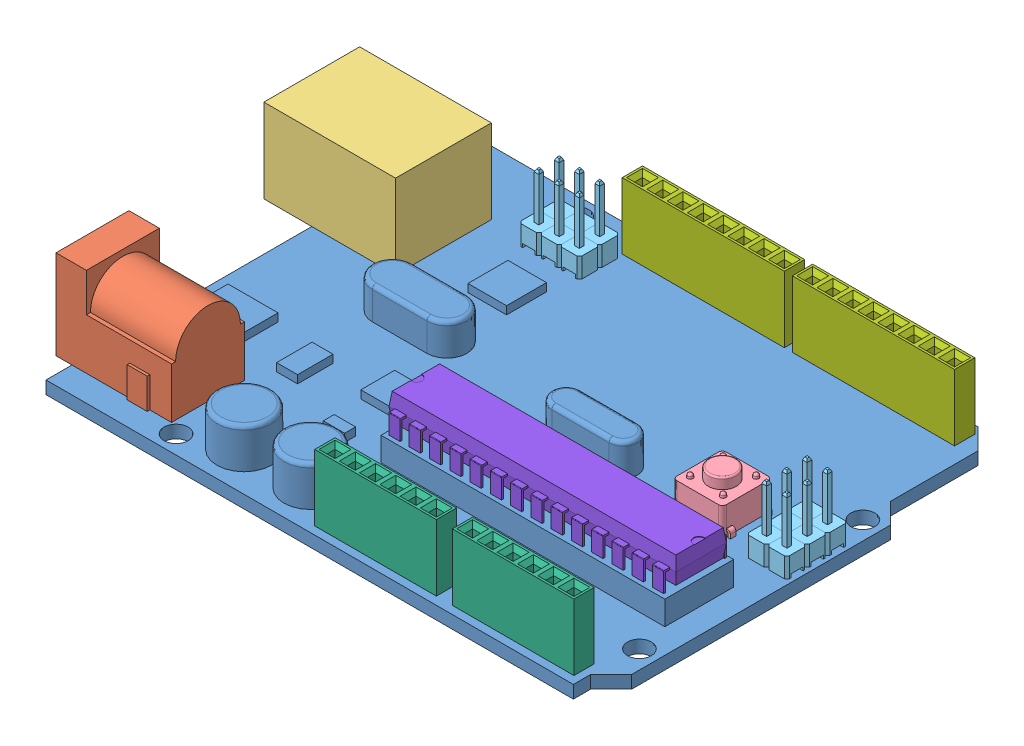
SolidWorks assembly User Library-Arduino-UNO, configuration Predeterminado. Lengths in mm.
Overall size (74.65 14.9 53.3).
15 component instances, 8 part files, 43 mates.
Components (placement in the parent):
- User Library-Arduino-UNO_Arduino_UNO_PCB-1: User Library-Arduino-UNO_Arduino_UNO_PCB [Predeterminado] at (-41.2845 -4.4325 26.65) size (68.65 6.6 53.3)
- User Library-Arduino-UNO_User Library-Arduino Mega_DC POWER JACK-1: User Library-Arduino-UNO_User Library-Arduino Mega_DC POWER JACK [Default] at (-43.2845 -2.8325 18.828) x (0 0 1) z (-1 0 0) size (9.47 14.78 14.48)
- User Library-Arduino-UNO_User Library-Arduino Mega_USB SM host-1: User Library-Arduino-UNO_User Library-Arduino Mega_USB SM host [Default] at (-39.0345 2.4175 -12.65) x (0 0 1) z (-1 0 0) size (14.86 14.22 16.5)
- User Library-Arduino-UNO_User Library-Arduino Mega_tactile BUTTON-1: User Library-Arduino-UNO_User Library-Arduino Mega_tactile BUTTON [Default] at (15.2655 -2.8325 -1.55) x (1 0 0) z (0 1 0) size (7.9 6.2 7.35)
- User Library-Arduino-UNO_User Library-Arduino Mega_Header Vertical 2_54mm Pitch4-1-3: User Library-Arduino-UNO_User Library-Arduino Mega_Header Vertical 2_54mm Pitch4-1 [2 Way] at (-21.2045 -2.8325 -20.11) size (2.54 9.3 5.08)
- User Library-Arduino-UNO_User Library-Arduino Mega_Header Vertical 2_54mm Pitch4-1-4: User Library-Arduino-UNO_User Library-Arduino Mega_Header Vertical 2_54mm Pitch4-1 [2 Way] at (-23.7445 -2.8325 -20.11) size (2.54 9.3 5.08)
- User Library-Arduino-UNO_User Library-Arduino Mega_Header Vertical 2_54mm Pitch4-1-5: User Library-Arduino-UNO_User Library-Arduino Mega_Header Vertical 2_54mm Pitch4-1 [2 Way] at (-26.2845 -2.8325 -20.11) size (2.54 9.3 5.08)
- User Library-Arduino-UNO_User Library-Arduino Mega_Header Vertical 2_54mm Pitch4-1-6: User Library-Arduino-UNO_User Library-Arduino Mega_Header Vertical 2_54mm Pitch4-1 [2 Way] at (24.3255 -2.8325 -3.11) x (0 0 -1) z (1 0 0) size (2.54 9.3 5.08)
- User Library-Arduino-UNO_User Library-Arduino Mega_Header Vertical 2_54mm Pitch4-1-7: User Library-Arduino-UNO_User Library-Arduino Mega_Header Vertical 2_54mm Pitch4-1 [2 Way] at (24.3255 -2.8325 1.97) x (0 0 -1) z (1 0 0) size (2.54 9.3 5.08)
- User Library-Arduino-UNO_User Library-Arduino Mega_Header Vertical 2_54mm Pitch4-1-8: User Library-Arduino-UNO_User Library-Arduino Mega_Header Vertical 2_54mm Pitch4-1 [2 Way] at (24.3255 -2.8325 -0.57) x (0 0 -1) z (1 0 0) size (2.54 9.3 5.08)
- User Library-Arduino-UNO_User Library-Arduino Mega_PIN HEADER FEMALE 6-1: User Library-Arduino-UNO_User Library-Arduino Mega_PIN HEADER FEMALE 6 [Default] at (-7.3445 -2.8325 24.38) size (15.24 8.3 2.54)
- User Library-Arduino-UNO_User Library-Arduino Mega_PIN HEADER FEMALE 6-2: User Library-Arduino-UNO_User Library-Arduino Mega_PIN HEADER FEMALE 6 [Default] at (9.8955 -2.8325 24.38) size (15.24 8.3 2.54)
- User Library-Arduino-UNO_User Library-Arduino Mega_PIN HEADER FEMALE 8-1: User Library-Arduino-UNO_User Library-Arduino Mega_PIN HEADER FEMALE 8 [Default] at (-17.5745 -2.8325 -24.38) size (20.32 8.3 2.54)
- User Library-Arduino-UNO_User Library-Arduino Mega_PIN HEADER FEMALE 8-2: User Library-Arduino-UNO_User Library-Arduino Mega_PIN HEADER FEMALE 8 [Default] at (3.7455 -2.8325 -24.38) size (20.32 8.3 2.54)
- User Library-Arduino-UNO_User Library-28 pin dip-1: User Library-Arduino-UNO_User Library-28 pin dip [Default] at (1.315 2.5165 10.213) x (0 0 -1) z (1 0 0) size (7.87 6.22 35.94)
Mates (geometry in assembly coordinates):
- Coincidente1: coincident anti-aligned: plane of User Library-Arduino-UNO_Arduino_UNO_PCB-1 through (-41.2845 -2.8325 -26.65) normal (0 1 0); plane of User Library-Arduino-UNO_User Library-Arduino Mega_DC POWER JACK-1 through (-39.4745 -2.8325 14.256) normal (0 -1 0)
- Distancia1: distance = 2 mm aligned: plane of User Library-Arduino-UNO_Arduino_UNO_PCB-1 through (-41.2845 -2.8325 26.65) normal (-1 0 0); plane of User Library-Arduino-UNO_User Library-Arduino Mega_DC POWER JACK-1 through (-43.2845 8.3435 14.256) normal (-1 0 0)
- Distancia2: distance = 3.25 mm aligned: plane of User Library-Arduino-UNO_User Library-Arduino Mega_DC POWER JACK-1 through (-39.4745 -2.8325 23.4) normal (0 0 1); plane of User Library-Arduino-UNO_Arduino_UNO_PCB-1 through (24.7955 -2.8325 26.65) normal (0 0 1)
- Coincidente4: coincident anti-aligned: plane of User Library-Arduino-UNO_Arduino_UNO_PCB-1 through (-41.2845 -2.8325 -26.65) normal (0 1 0); plane of User Library-Arduino-UNO_User Library-Arduino Mega_USB SM host-1 through (-47.2845 -2.8325 -18.65) normal (0 -1 0)
- Distancia3: distance = 6 mm aligned: plane of User Library-Arduino-UNO_User Library-Arduino Mega_USB SM host-1 through (-47.2845 -2.8325 -18.65) normal (-1 0 0); plane of User Library-Arduino-UNO_Arduino_UNO_PCB-1 through (-41.2845 -2.8325 26.65) normal (-1 0 0)
- Distancia4: distance = 8 mm aligned: plane of User Library-Arduino-UNO_User Library-Arduino Mega_USB SM host-1 through (-47.2845 7.6675 -18.65) normal (0 0 -1); plane of User Library-Arduino-UNO_Arduino_UNO_PCB-1 through (-41.2845 -2.8325 -26.65) normal (0 0 -1)
- Coincidente7: coincident anti-aligned: plane of User Library-Arduino-UNO_Arduino_UNO_PCB-1 through (-41.2845 -2.8325 -26.65) normal (0 1 0); plane of User Library-Arduino-UNO_User Library-Arduino Mega_tactile BUTTON-1 through (12.1655 -2.8325 -4.65) normal (0 -1 0)
- Distancia5: distance = 9 mm aligned: plane of User Library-Arduino-UNO_User Library-Arduino Mega_tactile BUTTON-1 through (18.3655 0.6675 1.55) normal (1 0 0); plane of User Library-Arduino-UNO_Arduino_UNO_PCB-1 through (27.3655 -2.8325 -13.0888) normal (1 0 0)
- Distancia6: distance = 22 mm aligned: plane of User Library-Arduino-UNO_User Library-Arduino Mega_tactile BUTTON-1 through (12.1655 0.6675 -4.65) normal (0 0 -1); plane of User Library-Arduino-UNO_Arduino_UNO_PCB-1 through (-41.2845 -2.8325 -26.65) normal (0 0 -1)
- Coincidente10: coincident aligned: plane of User Library-Arduino-UNO_User Library-Arduino Mega_Header Vertical 2_54mm Pitch4-1-3 through (-22.1745 -0.3325 -18.84) normal (0 1 0); plane of User Library-Arduino-UNO_User Library-Arduino Mega_Header Vertical 2_54mm Pitch4-1-4 through (-24.7145 -0.3325 -18.84) normal (0 1 0)
- Coincidente11: coincident aligned: plane of User Library-Arduino-UNO_User Library-Arduino Mega_Header Vertical 2_54mm Pitch4-1-4 through (-24.7145 -0.3325 -18.84) normal (0 1 0); plane of User Library-Arduino-UNO_User Library-Arduino Mega_Header Vertical 2_54mm Pitch4-1-5 through (-27.2545 -0.3325 -18.84) normal (0 1 0)
- Coincidente12: coincident aligned: plane of User Library-Arduino-UNO_User Library-Arduino Mega_Header Vertical 2_54mm Pitch4-1-4 through (-23.4445 -0.3325 -17.57) normal (0 0 1); plane of User Library-Arduino-UNO_User Library-Arduino Mega_Header Vertical 2_54mm Pitch4-1-5 through (-25.9845 -0.3325 -17.57) normal (0 0 1)
- Coincidente13: coincident aligned: plane of User Library-Arduino-UNO_User Library-Arduino Mega_Header Vertical 2_54mm Pitch4-1-3 through (-20.9045 -0.3325 -17.57) normal (0 0 1); plane of User Library-Arduino-UNO_User Library-Arduino Mega_Header Vertical 2_54mm Pitch4-1-4 through (-23.4445 -0.3325 -17.57) normal (0 0 1)
- Coincidente14: coincident anti-aligned: plane of User Library-Arduino-UNO_User Library-Arduino Mega_Header Vertical 2_54mm Pitch4-1-3 through (-21.2045 -0.3325 -19.81) normal (-1 0 0); plane of User Library-Arduino-UNO_User Library-Arduino Mega_Header Vertical 2_54mm Pitch4-1-4 through (-21.2045 -0.3325 -17.87) normal (1 0 0)
- Coincidente15: coincident anti-aligned: plane of User Library-Arduino-UNO_User Library-Arduino Mega_Header Vertical 2_54mm Pitch4-1-4 through (-23.7445 -0.3325 -19.81) normal (-1 0 0); plane of User Library-Arduino-UNO_User Library-Arduino Mega_Header Vertical 2_54mm Pitch4-1-5 through (-23.7445 -0.3325 -17.87) normal (1 0 0)
- Coincidente16: coincident anti-aligned: plane of User Library-Arduino-UNO_Arduino_UNO_PCB-1 through (-41.2845 -2.8325 -26.65) normal (0 1 0); plane of User Library-Arduino-UNO_User Library-Arduino Mega_Header Vertical 2_54mm Pitch4-1-3 through (-22.1745 -2.8325 -18.84) normal (0 -1 0)
- Coincidente17: coincident aligned: plane of User Library-Arduino-UNO_User Library-Arduino Mega_Header Vertical 2_54mm Pitch4-1-7 through (25.5955 -0.3325 2.94) normal (0 1 0); plane of User Library-Arduino-UNO_User Library-Arduino Mega_Header Vertical 2_54mm Pitch4-1-8 through (23.0555 -0.3325 0.4) normal (0 1 0)
- Coincidente18: coincident aligned: plane of User Library-Arduino-UNO_User Library-Arduino Mega_Header Vertical 2_54mm Pitch4-1-6 through (25.5955 -0.3325 -2.14) normal (0 1 0); plane of User Library-Arduino-UNO_User Library-Arduino Mega_Header Vertical 2_54mm Pitch4-1-7 through (25.5955 -0.3325 2.94) normal (0 1 0)
- Coincidente19: coincident aligned: plane of User Library-Arduino-UNO_User Library-Arduino Mega_Header Vertical 2_54mm Pitch4-1-6 through (26.8655 -0.3325 -3.41) normal (1 0 0); plane of User Library-Arduino-UNO_User Library-Arduino Mega_Header Vertical 2_54mm Pitch4-1-7 through (26.8655 -0.3325 1.67) normal (1 0 0)
- Coincidente20: coincident aligned: plane of User Library-Arduino-UNO_User Library-Arduino Mega_Header Vertical 2_54mm Pitch4-1-7 through (26.8655 -0.3325 1.67) normal (1 0 0); plane of User Library-Arduino-UNO_User Library-Arduino Mega_Header Vertical 2_54mm Pitch4-1-8 through (26.8655 -0.3325 -0.87) normal (1 0 0)
- Coincidente21: coincident anti-aligned: plane of User Library-Arduino-UNO_User Library-Arduino Mega_Header Vertical 2_54mm Pitch4-1-6 through (24.6255 -0.3325 -3.11) normal (0 0 1); plane of User Library-Arduino-UNO_User Library-Arduino Mega_Header Vertical 2_54mm Pitch4-1-8 through (26.5655 -0.3325 -3.11) normal (0 0 -1)
- Coincidente22: coincident anti-aligned: plane of User Library-Arduino-UNO_User Library-Arduino Mega_Header Vertical 2_54mm Pitch4-1-7 through (26.5655 -0.3325 -0.57) normal (0 0 -1); plane of User Library-Arduino-UNO_User Library-Arduino Mega_Header Vertical 2_54mm Pitch4-1-8 through (24.6255 -0.3325 -0.57) normal (0 0 1)
- Coincidente23: coincident anti-aligned: plane of User Library-Arduino-UNO_Arduino_UNO_PCB-1 through (-41.2845 -2.8325 -26.65) normal (0 1 0); plane of User Library-Arduino-UNO_User Library-Arduino Mega_Header Vertical 2_54mm Pitch4-1-6 through (25.5955 -2.8325 -2.14) normal (0 -1 0)
- Distancia7: distance = 0.5 mm aligned: plane of User Library-Arduino-UNO_User Library-Arduino Mega_Header Vertical 2_54mm Pitch4-1-8 through (26.8655 -0.3325 -0.87) normal (1 0 0); plane of User Library-Arduino-UNO_Arduino_UNO_PCB-1 through (27.3655 -2.8325 -13.0888) normal (1 0 0)
- Distancia8: distance = 21 mm aligned: plane of User Library-Arduino-UNO_User Library-Arduino Mega_Header Vertical 2_54mm Pitch4-1-6 through (26.5655 -0.3325 -5.65) normal (0 0 -1); plane of User Library-Arduino-UNO_Arduino_UNO_PCB-1 through (-41.2845 -2.8325 -26.65) normal (0 0 -1)
- Distancia9: distance = 4 mm aligned: plane of User Library-Arduino-UNO_User Library-Arduino Mega_Header Vertical 2_54mm Pitch4-1-4 through (-21.5045 -0.3325 -22.65) normal (0 0 -1); plane of User Library-Arduino-UNO_Arduino_UNO_PCB-1 through (-41.2845 -2.8325 -26.65) normal (0 0 -1)
- Distancia10: distance = 15 mm aligned: plane of User Library-Arduino-UNO_User Library-Arduino Mega_Header Vertical 2_54mm Pitch4-1-5 through (-26.2845 -0.3325 -22.35) normal (-1 0 0); plane of User Library-Arduino-UNO_Arduino_UNO_PCB-1 through (-41.2845 -2.8325 26.65) normal (-1 0 0)
- Coincidente29: coincident aligned: plane of User Library-Arduino-UNO_User Library-Arduino Mega_PIN HEADER FEMALE 6-1 through (-8.6145 5.4675 25.65) normal (0 1 0); plane of User Library-Arduino-UNO_User Library-Arduino Mega_PIN HEADER FEMALE 6-2 through (8.6255 5.4675 25.65) normal (0 1 0)
- Coincidente30: coincident aligned: plane of User Library-Arduino-UNO_User Library-Arduino Mega_PIN HEADER FEMALE 8-1 through (-18.8445 5.4675 -23.11) normal (0 1 0); plane of User Library-Arduino-UNO_User Library-Arduino Mega_PIN HEADER FEMALE 8-2 through (2.4755 5.4675 -23.11) normal (0 1 0)
- Coincidente31: coincident anti-aligned: plane of User Library-Arduino-UNO_Arduino_UNO_PCB-1 through (-41.2845 -2.8325 -26.65) normal (0 1 0); plane of User Library-Arduino-UNO_User Library-Arduino Mega_PIN HEADER FEMALE 8-1 through (-18.8445 -2.8325 -23.11) normal (0 -1 0)
- Coincidente32: coincident aligned: plane of User Library-Arduino-UNO_User Library-Arduino Mega_PIN HEADER FEMALE 8-1 through (-16.3045 5.4675 -23.11) normal (0 0 1); plane of User Library-Arduino-UNO_User Library-Arduino Mega_PIN HEADER FEMALE 8-2 through (5.0155 5.4675 -23.11) normal (0 0 1)
- Coincidente33: coincident aligned: plane of User Library-Arduino-UNO_User Library-Arduino Mega_PIN HEADER FEMALE 6-1 through (-6.0745 5.4675 25.65) normal (0 0 1); plane of User Library-Arduino-UNO_User Library-Arduino Mega_PIN HEADER FEMALE 6-2 through (11.1655 5.4675 25.65) normal (0 0 1)
- Coincidente34: coincident anti-aligned: plane of User Library-Arduino-UNO_Arduino_UNO_PCB-1 through (-41.2845 -2.8325 -26.65) normal (0 1 0); plane of User Library-Arduino-UNO_User Library-Arduino Mega_PIN HEADER FEMALE 6-1 through (-8.6145 -2.8325 25.65) normal (0 -1 0)
- Distancia11: distance = 2 mm anti-aligned: plane of User Library-Arduino-UNO_User Library-Arduino Mega_PIN HEADER FEMALE 6-2 through (8.6255 5.4675 25.65) normal (-1 0 0); plane of User Library-Arduino-UNO_User Library-Arduino Mega_PIN HEADER FEMALE 6-1 through (6.6255 5.4675 25.65) normal (1 0 0)
- Distancia12: distance = 1 mm anti-aligned: plane of User Library-Arduino-UNO_User Library-Arduino Mega_PIN HEADER FEMALE 8-1 through (1.4755 5.4675 -23.11) normal (1 0 0); plane of User Library-Arduino-UNO_User Library-Arduino Mega_PIN HEADER FEMALE 8-2 through (2.4755 5.4675 -23.11) normal (-1 0 0)
- Distancia13: distance = 1 mm aligned: plane of User Library-Arduino-UNO_User Library-Arduino Mega_PIN HEADER FEMALE 6-2 through (11.1655 5.4675 25.65) normal (0 0 1); plane of User Library-Arduino-UNO_Arduino_UNO_PCB-1 through (24.7955 -2.8325 26.65) normal (0 0 1)
- Distancia14: distance = 3.5 mm aligned: plane of User Library-Arduino-UNO_User Library-Arduino Mega_PIN HEADER FEMALE 6-2 through (23.8655 5.4675 25.65) normal (1 0 0); plane of User Library-Arduino-UNO_Arduino_UNO_PCB-1 through (27.3655 -2.8325 -13.0888) normal (1 0 0)
- Distancia15: distance = 1 mm aligned: plane of User Library-Arduino-UNO_Arduino_UNO_PCB-1 through (-41.2845 -2.8325 -26.65) normal (0 0 -1); plane of User Library-Arduino-UNO_User Library-Arduino Mega_PIN HEADER FEMALE 8-2 through (5.0155 5.4675 -25.65) normal (0 0 -1)
- Distancia16: distance = 2 mm aligned: plane of User Library-Arduino-UNO_User Library-Arduino Mega_PIN HEADER FEMALE 8-2 through (22.7955 5.4675 -23.11) normal (1 0 0); plane of User Library-Arduino-UNO_Arduino_UNO_PCB-1 through (24.7955 -2.8325 -26.65) normal (1 0 0)
- Distancia18: distance = 7 mm aligned: plane of User Library-Arduino-UNO_Arduino_UNO_PCB-1 through (-41.2845 -2.8325 -26.65) normal (0 1 0); plane of User Library-Arduino-UNO_User Library-28 pin dip-1 through (14.2055 4.1675 13.388) normal (0 1 0)
- Paralelo1: parallel anti-aligned: plane of User Library-Arduino-UNO_Arduino_UNO_PCB-1 through (24.7955 -2.8325 26.65) normal (0 0 1); plane of User Library-Arduino-UNO_User Library-28 pin dip-1 through (1.8865 2.6435 6.276) normal (0 0 -1)
- Distancia19: distance = 3 mm: plane of User Library-Arduino-UNO_Arduino_UNO_PCB-1 through (27.3655 -2.8325 -13.0888) normal (1 0 0); line of User Library-Arduino-UNO_User Library-28 pin dip-1 through (24.3655 2.5165 7.038) axis (0 0 1)
- Distancia20: distance = 12.5 mm aligned: plane of User Library-Arduino-UNO_User Library-28 pin dip-1 through (21.0635 2.6435 14.15) normal (0 0 1); plane of User Library-Arduino-UNO_Arduino_UNO_PCB-1 through (24.7955 -2.8325 26.65) normal (0 0 1)
